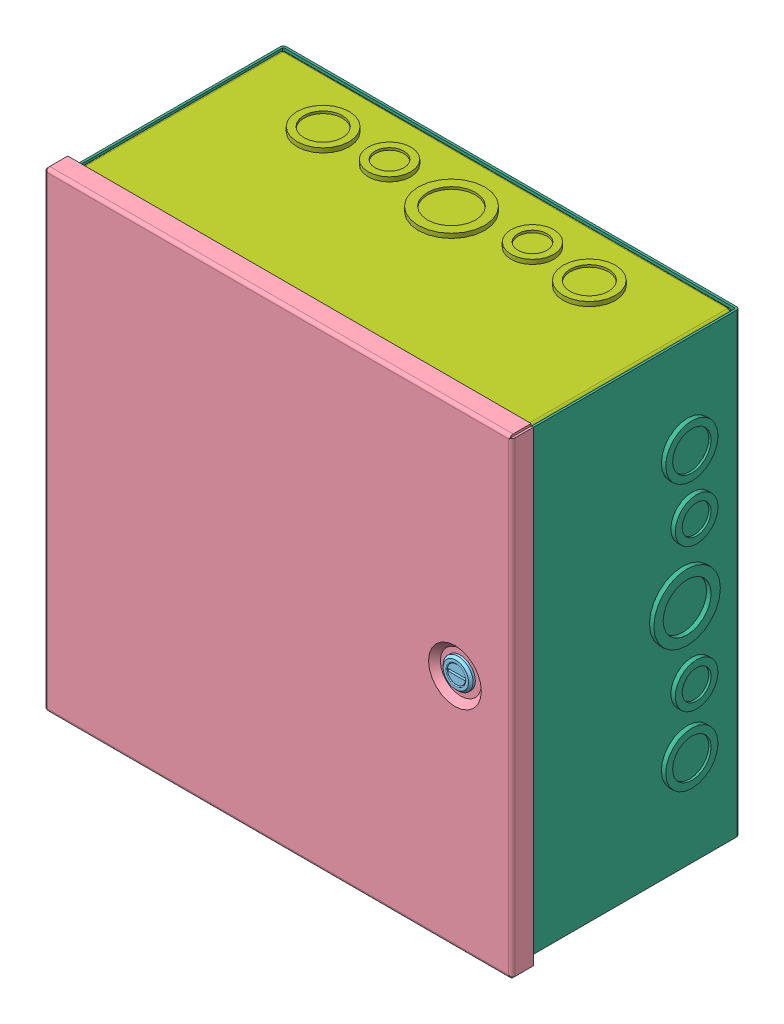
SolidWorks assembly CHKO12126, configuration Défaut. Lengths in mm.
Overall size (316.05 314.45 155.4).
17 component instances, 9 part files, 0 mates.
Components (placement in the parent):
- CHKO12126.stp-1: CHKO12126.stp [Défaut] at origin size (316.05 314.45 155.4)
  - COM55100-7.stp-1: COM55100-7.stp [Défaut] at (-0.5461 0.0127 155.3972) size (316.05 314.45 42.76)
    - HNG11000.stp-1: HNG11000.stp [Défaut] at (-152.8572 114.2873 -1.4478) x (1 0 0) z (0 0 -1) size (7.99 54.61 41.3)
      - HNG11000-3.stp-1: HNG11000-3.stp [Défaut] at (-3.4925 0 20.6502) x (0 0 -1) z (0 1 0) size (3.17 3.17 54.61)
      - HNG11000-2.stp-1: HNG11000-2.stp [Défaut] at (1.0033 0 41.3004) x (1 0 0) z (0 0 -1) size (7.99 50.8 24.14)
      - HNG11000-0.stp-1: HNG11000-0.stp [Défaut] at origin size (6.99 50.8 24.14)
    - HNG11000.stp-2: HNG11000.stp [Défaut] at (-152.8572 -114.3127 -1.4478) x (1 0 0) z (0 0 -1) size (7.99 54.61 41.3)
      - HNG11000-3.stp-1: HNG11000-3.stp [Défaut] at (-3.4925 0 20.6502) x (0 0 -1) z (0 1 0) size (3.17 3.17 54.61)
      - HNG11000-2.stp-1: HNG11000-2.stp [Défaut] at (1.0033 0 41.3004) x (1 0 0) z (0 0 -1) size (7.99 50.8 24.14)
      - HNG11000-0.stp-1: HNG11000-0.stp [Défaut] at origin size (6.99 50.8 24.14)
    - COM56469.stp-1: COM56469.stp [Défaut] at origin size (312.42 314.45 14.28)
  - LOC13368.stp-1: LOC13368.stp [Défaut] at (117.2239 0.0127 151.4348) x (0 1 0) z (0 0 1) size (24.95 39.99 23.49)
  - Com55565-5.stp-1: Com55565-5.stp [Défaut] at origin size (310.74 304.8 152.4)
  - COM55087-4.stp-1: COM55087-4.stp [Défaut] at (0 152.4 102.616) x (-1 0 0) z (0 1 0) size (301.24 150.37 18.85)
  - COM55087-4.stp-2: COM55087-4.stp [Défaut] at (0 -152.4 102.616) x (1 0 0) z (0 -1 0) size (301.24 150.37 18.85)
  - QLB20292.stp-1: QLB20292.stp [Défaut] at (-150.9522 -74.7522 106.5022) x (0 1 0) z (0 0 1) size (101.6 1.07 63.5)
  - SCS19515.stp-1: SCS19515.stp [Défaut] at origin size (9.53 9.53 12.42)
